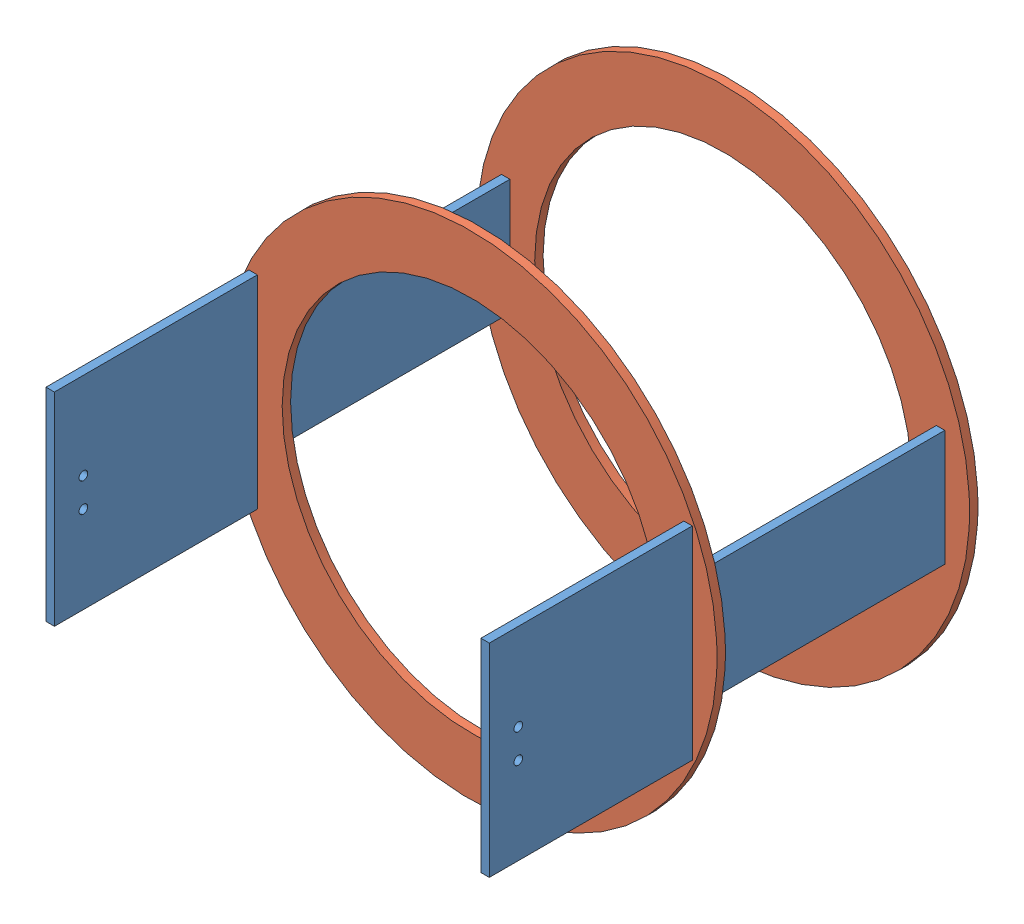
SolidWorks assembly Assem1, configuration Default. Lengths in mm.
Overall size (170 170 160).
4 component instances, 2 part files, 9 mates.
Components (placement in the parent):
- arm_side-1: arm_side [Default] at (61.6277 91.8956 160.3378) size (2.9 70 160)
- arm_ring-1: arm_ring [Default] at (-11.9223 91.8956 122.4378) size (170 170 2.9)
- arm_side-2: arm_side [Default] at (-88.3723 91.8956 160.3378) size (2.9 70 160)
- arm_ring-2: arm_ring [Default] at (-11.9223 91.8956 35.3378) size (170 170 2.9)
Mates (geometry in assembly coordinates):
- Coincident3: coincident anti-aligned: plane of arm_side-1 through (64.5277 71.8956 125.3378) normal (0 0 -1); plane of arm_ring-1 through (-11.9223 91.8956 125.3378) normal (0 0 1)
- Coincident4: coincident anti-aligned: plane of arm_side-1 through (64.5277 71.8956 35.3378) normal (0 -1 0); plane of arm_ring-1 through (64.5277 71.8956 125.3378) normal (0 1 0)
- Coincident5: coincident anti-aligned: plane of arm_side-1 through (61.6277 91.8956 160.3378) normal (-1 0 0); plane of arm_ring-1 through (61.6277 111.8956 125.3378) normal (1 0 0)
- Coincident6: coincident anti-aligned: plane of arm_ring-1 through (-11.9223 91.8956 125.3378) normal (0 0 1); plane of arm_side-2 through (-85.4723 71.8956 125.3378) normal (0 0 -1)
- Coincident7: coincident anti-aligned: plane of arm_ring-1 through (-85.4723 111.8956 125.3378) normal (-1 0 0); plane of arm_side-2 through (-85.4723 91.8956 160.3378) normal (1 0 0)
- Coincident8: coincident anti-aligned: plane of arm_ring-1 through (-88.3723 111.8956 125.3378) normal (0 -1 0); plane of arm_side-2 through (-85.4723 111.8956 35.3378) normal (0 1 0)
- Coincident10: coincident: plane of arm_side-2 through (-85.4723 91.8956 160.3378) normal (1 0 0); plane of arm_ring-2 through (-85.4723 111.8956 38.2378) normal (-1 0 0)
- Coincident11: coincident: plane of arm_side-2 through (-85.4723 111.8956 35.3378) normal (0 1 0); plane of arm_ring-2 through (-88.3723 111.8956 38.2378) normal (0 -1 0)
- Coincident12: coincident aligned: plane of arm_side-2 through (-85.4723 71.8956 35.3378) normal (0 0 -1); plane of arm_ring-2 through (-11.9223 91.8956 35.3378) normal (0 0 -1)
